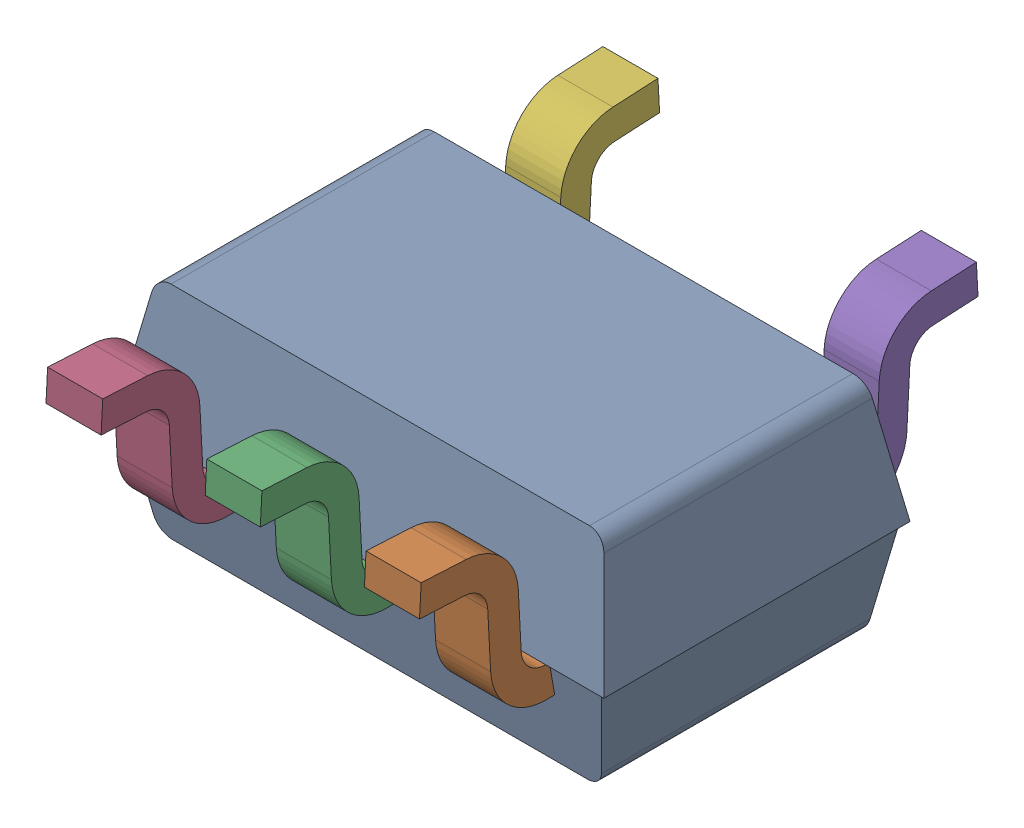
SolidWorks assembly DCK0005AakaMAA05A, configuration Default. Lengths in mm.
Overall size (2 0.95 2.28).
7 component instances, 6 part files, 0 mates.
Components (placement in the parent):
- BODY_MAA05-1: BODY_MAA05 [Default] at origin size (2 0.9 1.25)
- LEADS_MAA05A-1: LEADS_MAA05A [Default] at (0.65 0 0) x (0 0 1) z (1 0 0) size (2.28 0.67 1.53)
  - LEADS_MAA05A_3-1: LEADS_MAA05A_3 [Default] at origin size (0.55 0.67 0.23)
  - LEADS_MAA05A_4-1: LEADS_MAA05A_4 [Default] at origin size (0.55 0.67 0.23)
  - LEADS_MAA05A_5-1: LEADS_MAA05A_5 [Default] at origin size (0.55 0.67 0.23)
  - LEADS_MAA05A_6-1: LEADS_MAA05A_6 [Default] at origin size (0.55 0.67 0.23)
  - LEADS_MAA05A_7-1: LEADS_MAA05A_7 [Default] at origin size (0.55 0.67 0.23)
